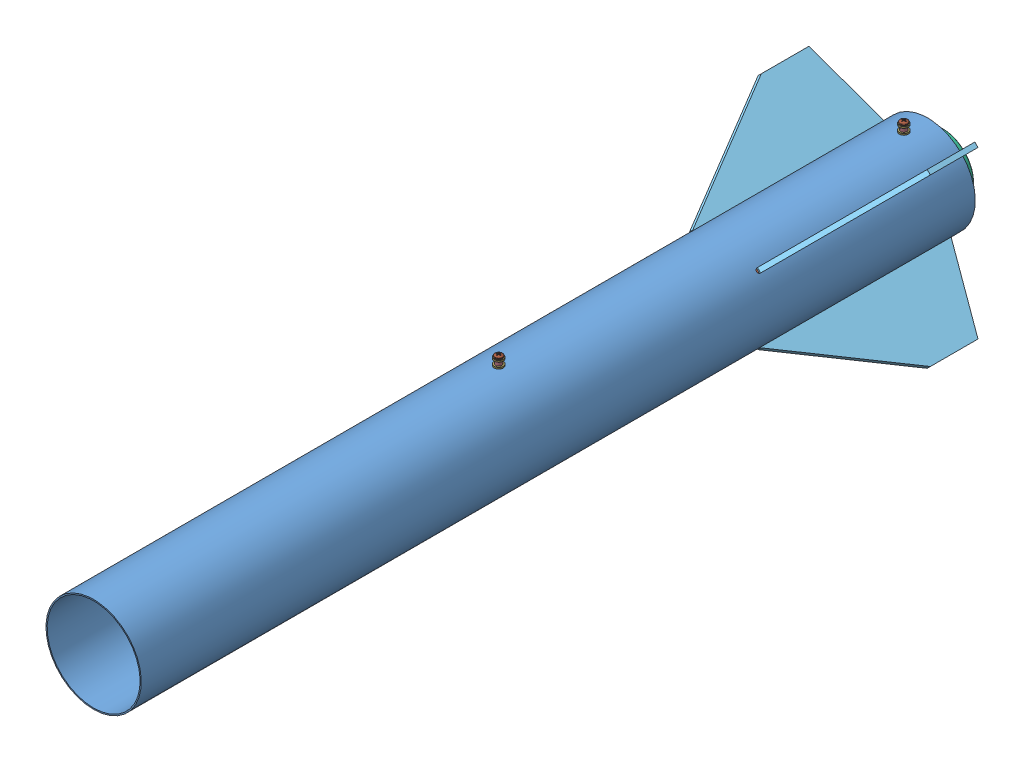
SolidWorks assembly booster, configuration Default. Lengths in mm.
Overall size (201.51 201.51 916.48).
27 component instances, 14 part files, 34 mates.
Components (placement in the parent):
- booster_airframe-1: booster_airframe [Default] at (271.0916 449.228 -1243.3556) x (-1 0 0) z (0 1 0) size (101.6 889 101.6)
- centering_ring-1: centering_ring [Default] at (271.0916 449.228 -1233.8306) x (-0.542471 0.840075 0) z (0 0 1) size (99.06 99.06 3.17)
- centering_ring-2: centering_ring [Default] at (271.0916 449.228 -1027.4556) x (0.715344 -0.698772 0) z (0 0 1) size (99.06 99.06 3.17)
- centering_ring_top-1: centering_ring_top [Default] at (271.0916 449.228 -954.4306) x (0.623786 -0.781595 0) z (0 0 1) size (99.06 99.06 3.17)
- motor_mount-1: motor_mount [Default] at (271.0916 449.228 -941.7306) x (1 0 0) z (0 1 0) size (56.95 304.8 56.95)
- fin-1: fin [Default] at (250.9579 429.0943 -1027.4556) x (0 0 -1) z (0.707107 0.707107 0) size (203.2 4.76 111.63)
- fin-2: fin [Default] at (250.9579 469.3617 -1027.4556) x (0 0 -1) z (0.707107 -0.707107 0) size (203.2 4.76 111.63)
- fin-3: fin [Default] at (291.2253 469.3617 -1027.4556) x (0 0 -1) z (-0.707107 -0.707107 0) size (203.2 4.76 111.63)
- fin-4: fin [Default] at (291.2253 429.0943 -1027.4556) x (0 0 -1) z (-0.707107 0.707107 0) size (203.2 4.76 111.63)
- motor_retainer-1: motor_retainer [Default] at (252.0197 502.7491 -1287.4823) x (1 0 0) z (0 -1 0) size (68.51 25.72 68.51)
  - retainer_cap-1: retainer_cap [Default] at (19.0719 27.9343 53.5211) size (66.55 15.37 66.55)
  - retainer_body-1: retainer_body [Default] at (19.0719 53.6518 53.5211) x (-0.086968 0 0.996211) z (0.996211 0 0.086968) size (63.25 24.13 63.25)
- motor_case-1: motor_case [Default] at (271.0916 449.228 -1248.1054) x (0.316501 -0.948592 0) z (-0.948592 -0.316501 0) size (57.79 600.33 57.79)
- u_bolt_booster-1: u_bolt_booster [2936T68] at (271.0916 411.128 -936.3066) x (1 0 0) z (0 1 0) size (47.62 51.22 19.05)
- 1-4_nut-1: 1-4_nut [95462A029] at (255.2166 411.128 -948.4774) size (11.11 12.83 6.51)
- 1-4_nut-2: 1-4_nut [95462A029] at (286.9666 411.128 -948.4774) size (11.11 12.83 6.51)
- railbutton-1: railbutton [Default] at (271.0916 495.2655 -786.1556) x (0 0 -1) z (0 1 0) size (12.45 12.45 15.68)
  - railbutton_screw-1: railbutton_screw [91772A194] at origin size (8.18 8.18 15.68)
  - railbutton_washer-1: railbutton_washer [Default] at (0 0 11.1125) x (-0.923728 -0.383049 0) z (-0.383049 0.923728 0) size (9.53 1.59 9.53)
  - railbutton_spacer-1: railbutton_spacer [Default] at (0 0 11.1125) x (1 0 0) z (0 1 0) size (6.35 4.76 6.35)
  - railbutton_washer-2: railbutton_washer [Default] at (0 0 6.35) x (1 0 0) z (0 1 0) size (9.53 1.59 9.53)
- railbutton-2: railbutton [Default] at (271.0916 495.2655 -1217.9556) x (0 0 1) z (0 1 0) size (12.45 12.45 15.68)
  - railbutton_screw-1: railbutton_screw [91772A194] at origin size (8.18 8.18 15.68)
  - railbutton_washer-1: railbutton_washer [Default] at (0 0 11.1125) x (-0.923728 -0.383049 0) z (-0.383049 0.923728 0) size (9.53 1.59 9.53)
  - railbutton_spacer-1: railbutton_spacer [Default] at (0 0 11.1125) x (1 0 0) z (0 1 0) size (6.35 4.76 6.35)
  - railbutton_washer-2: railbutton_washer [Default] at (0 0 6.35) x (1 0 0) z (0 1 0) size (9.53 1.59 9.53)
- drogue-1: drogue [Default] at (271.0916 449.228 -619.7094) size (81.28 81.28 50.8)
Mates (geometry in assembly coordinates):
- Concentric1: concentric aligned: cylinder of booster_airframe-1 through (271.0916 449.228 -354.3556) axis (0 0 -1) radius 49.53; cylinder of Centering Ring-1 through (271.0916 449.228 -1230.6556) axis (0 0 -1) radius 49.53
- Distance1: distance = 9.525 mm aligned: plane of Centering Ring-1 through (271.0916 449.228 -1233.8306) normal (0 0 -1); plane of booster_airframe-1 through (271.0916 449.228 -1243.3556) normal (0 0 -1)
- Concentric2: concentric aligned: cylinder of booster_airframe-1 through (271.0916 449.228 -354.3556) axis (0 0 -1) radius 49.53; cylinder of Centering Ring-2 through (271.0916 449.228 -1024.2806) axis (0 0 -1) radius 49.53
- Distance2: distance = 215.9 mm aligned: plane of Centering Ring-2 through (271.0916 449.228 -1027.4556) normal (0 0 -1); plane of booster_airframe-1 through (271.0916 449.228 -1243.3556) normal (0 0 -1)
- Concentric3: concentric aligned: cylinder of booster_airframe-1 through (271.0916 449.228 -354.3556) axis (0 0 -1) radius 49.53; cylinder of centering_ring_top-1 through (271.0916 449.228 -951.2556) axis (0 0 -1) radius 49.53
- Concentric4: concentric anti-aligned: cylinder of centering_ring-1 through (271.0916 449.228 -1230.6556) axis (0 0 -1) radius 28.067; cylinder of motor_mount-1 through (271.0916 449.228 -1246.5306) axis (0 0 1) radius 28.4734
- Distance3: distance = 12.7 mm anti-aligned: plane of centering_ring_top-1 through (271.0916 449.228 -954.4306) normal (0 0 -1); plane of motor_mount-1 through (271.0916 449.228 -941.7306) normal (0 0 1)
- Distance4: distance = 12.7 mm aligned: plane of motor_mount-1 through (271.0916 449.228 -1246.5306) normal (0 0 -1); plane of centering_ring-1 through (271.0916 449.228 -1233.8306) normal (0 0 -1)
- Tangent1: tangent anti-aligned: cylinder of motor_mount-1 through (271.0916 449.228 -1246.5306) axis (0 0 1) radius 28.4734; plane of fin-1 through (252.6417 427.4105 -1230.6556) normal (0.707107 0.707107 0)
- Parallel1: parallel anti-aligned: cylinder of motor_mount-1 through (271.0916 449.228 -1246.5306) axis (0 0 1) radius 28.4734; line of fin-1 through (173.7052 348.474 -1154.4556) axis (0 0 -1)
- Coincident6: coincident anti-aligned: plane of centering_ring-2 through (271.0916 449.228 -1027.4556) normal (0 0 -1); plane of fin-1 through (252.6417 427.4105 -1027.4556) normal (0 0 1)
- Coincident7: coincident: point of motor_mount-1; moEndPointRef_w of fin-1
- Angle1: planar angle = 0.785398 rad aligned: plane of fin-1 through (252.6417 427.4105 -1027.4556) normal (0.707107 -0.707107 0)
- Concentric5: concentric aligned: cylinder of motor_mount-1 through (271.0916 449.228 -1246.5306) axis (0 0 1) radius 28.4734; cylinder of motor_retainer-1/retainer_body-1 through (271.0916 449.228 -1233.8306) axis (0 0 1) radius 28.956
- Coincident8: coincident anti-aligned: plane of centering_ring-1 through (271.0916 449.228 -1233.8306) normal (0 0 -1); plane of motor_retainer-1/retainer_body-1 through (268.5734 420.3817 -1233.8306) normal (0 0 1)
- Concentric6: concentric aligned: cylinder of motor_mount-1 through (271.0916 449.228 -1246.5306) axis (0 0 1) radius 27.3304; cylinder of motor_case-1 through (271.0916 449.228 -670.5094) axis (0 0 1) radius 26.9875
- Coincident9: coincident anti-aligned: plane of motor_retainer-1/retainer_body-1 through (268.5071 419.6226 -1248.1054) normal (0 0 -1); plane of motor_case-1 through (280.2361 421.8208 -1248.1054) normal (0 0 1)
- Coincident10: coincident anti-aligned: plane of centering_ring_top-1 through (271.0916 449.228 -954.4306) normal (0 0 -1); plane of u_bolt-1 through (247.2791 401.603 -954.4306) normal (0 0 1)
- Parallel2: parallel anti-aligned: plane of u_bolt-1 through (294.9041 401.603 -954.4306) normal (0 -1 0)
- Coincident12: coincident aligned: plane of motor_mount-1 through (271.0916 449.228 -941.7306) normal (1 0 0); plane of u_bolt-1 through (271.0916 411.128 -936.3066) normal (1 0 0)
- Distance5: distance = 38.1 mm aligned: plane of motor_mount-1 through (271.0916 449.228 -941.7306) normal (0 1 0); plane of u_bolt-1 through (271.0916 411.128 -936.3066) normal (0 1 0)
- Coincident14: coincident anti-aligned: plane of centering_ring_top-1 through (271.0916 449.228 -951.2556) normal (0 0 1); plane of 1-4_nut-1 through (249.6604 414.3359 -951.2556) normal (0 0 -1)
- Concentric7: concentric anti-aligned: circle of u_bolt-1; circle of 1-4_nut-1
- Coincident15: coincident anti-aligned: plane of centering_ring_top-1 through (271.0916 449.228 -951.2556) normal (0 0 1); plane of 1-4_nut-2 through (281.4104 414.3359 -951.2556) normal (0 0 -1)
- Concentric8: concentric anti-aligned: cylinder of u_bolt-1 through (286.9666 411.128 -936.3066) axis (0 0 -1) radius 3.175; circle of 1-4_nut-2
- Tangent2: tangent anti-aligned: cylinder of booster_airframe-1 through (271.0916 449.228 -354.3556) axis (0 0 -1) radius 50.8; plane of railbutton-1/washer-2 through (271.0916 500.028 -786.1556) normal (0 -1 0)
- Tangent3: tangent anti-aligned: cylinder of booster_airframe-1 through (271.0916 449.228 -354.3556) axis (0 0 -1) radius 50.8; plane of railbutton-2/washer-2 through (271.0916 500.028 -1217.9556) normal (0 -1 0)
- Coincident18: coincident: plane of booster_airframe-1 through (271.0916 449.228 -1243.3556) normal (-1 0 0); line of railbutton-2 through (271.0916 501.6155 -1217.9556) axis (0 1 0)
- Coincident19: coincident: plane of booster_airframe-1 through (271.0916 449.228 -1243.3556) normal (-1 0 0); line of railbutton-1 through (271.0916 501.6155 -786.1556) axis (0 1 0)
- Distance6: distance = 25.4 mm: line of railbutton-2 through (271.0916 501.6155 -1217.9556) axis (0 1 0); plane of booster_airframe-1 through (271.0916 449.228 -1243.3556) normal (0 0 -1)
- Distance7: distance = 457.2 mm: line of railbutton-1 through (271.0916 501.6155 -786.1556) axis (0 1 0); plane of booster_airframe-1 through (271.0916 449.228 -1243.3556) normal (0 0 -1)
- Coincident23: coincident aligned: plane of railbutton-1/screw-1 through (271.5996 510.8865 -786.1556) normal (-0.996195 0.087156 0); plane of railbutton-2/screw-1 through (271.5996 510.8865 -1217.9556) normal (-0.996195 0.087156 0)
- Concentric10: concentric aligned: cylinder of booster_airframe-1 through (271.0916 449.228 -354.3556) axis (0 0 -1) radius 49.53; cylinder of drogue-1 through (271.0916 449.228 -568.9094) axis (0 0 -1) radius 40.64
- Distance8: distance = 50.8 mm anti-aligned: plane of drogue-1 through (271.0916 449.228 -619.7094) normal (0 0 -1); plane of motor_case-1 through (275.1112 437.1809 -670.5094) normal (0 0 1)
